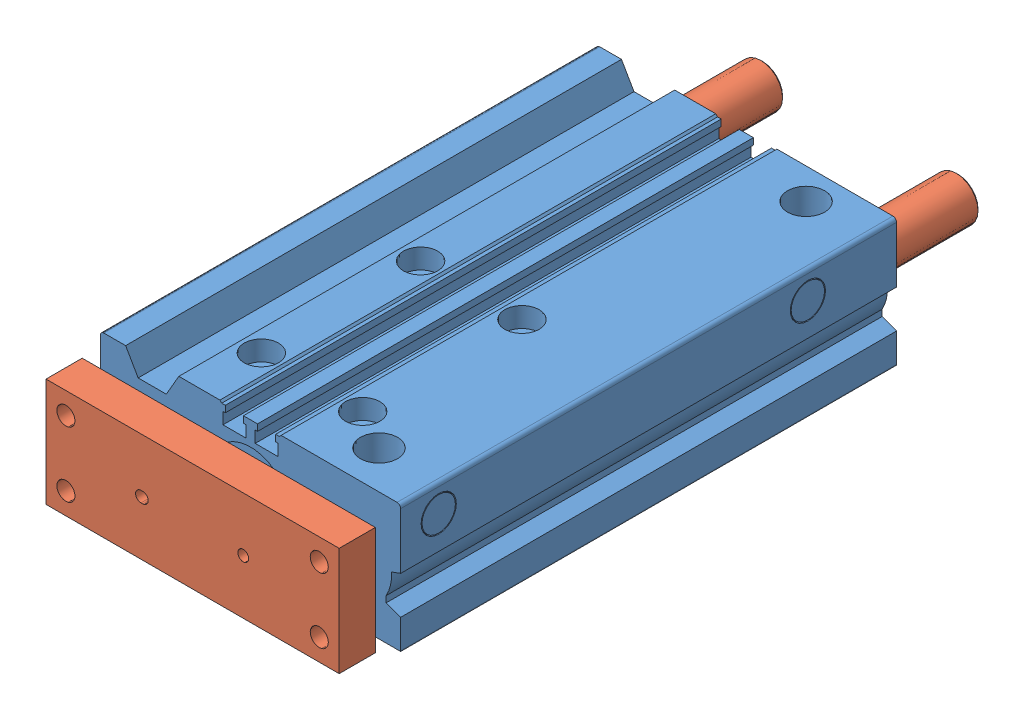
SolidWorks assembly COMPACT GUIDE CYLINDER, configuration MGPM20N-100. Lengths in mm.
Overall size (83 36 184.5).
2 component instances, 2 part files, 3 mates.
Components (placement in the parent):
- 5321-31 SMC MGPM20N-100_MGPTube-1: 5321-31 SMC MGPM20N-100_MGPTube [20M] at origin size (83 36 137)
- 5321-31 SMC MGPM20N-100_MGPRod-1: 5321-31 SMC MGPM20N-100_MGPRod [20M] at (0 0 -52.5) size (81 30 184.5)
Mates (geometry in assembly coordinates):
- Concentric1: concentric: cylinder of 5321-31 SMC MGPM20N-100_MGPTube-1 through (0 0 -14.2836) axis (0 0 1) radius 5.05; cylinder of 5321-31 SMC MGPM20N-100_MGPRod-1 through (0 0 88.6421) axis (0 0 -1) radius 5
- Parallel1: parallel: plane of 5321-31 SMC MGPM20N-100_MGPRod-1 through (0 0 -52.5) normal (0 1 0); plane of assembly through (0 0 0) normal (0 1 0)
- LimitDistance1: limit distance = 6 mm: plane of 5321-31 SMC MGPM20N-100_MGPTube-1 through (0 0 68.5) normal (0 0 1); plane of 5321-31 SMC MGPM20N-100_MGPRod-1 through (-40.5 -15 74.5) normal (0 0 -1)
